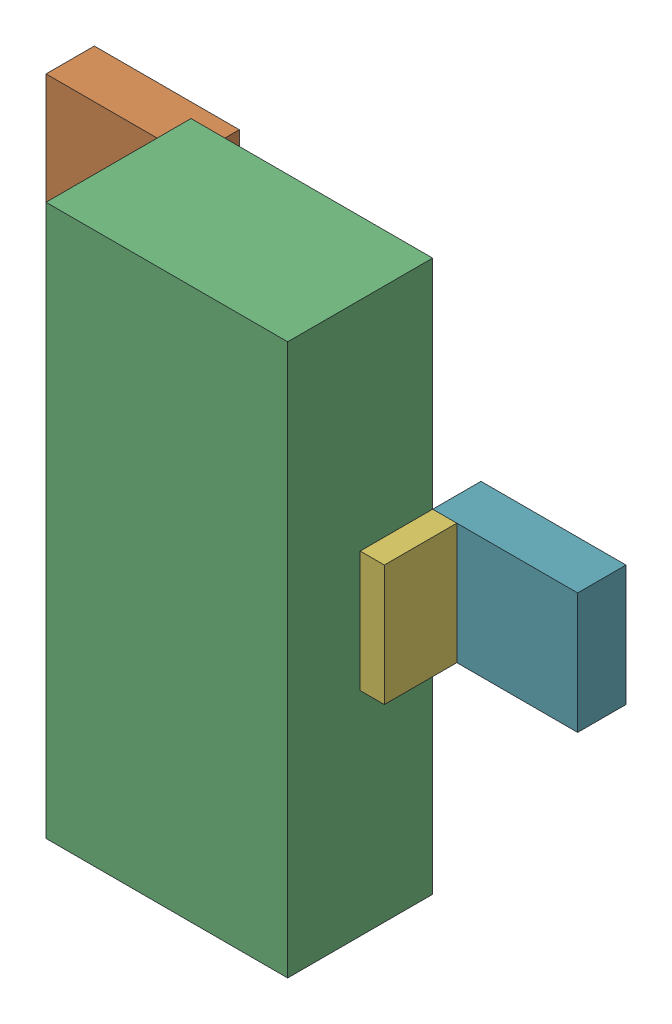
SolidWorks assembly Q5, configuration Default. Lengths in mm.
Overall size (2.79 2.9 1.02).
14 component instances, 3 part files, 0 mates.
Components (placement in the parent):
- 898052496-1: 898052496 [Default] at (26.7216 2.8829 0) size (0.76 0.64 0.25)
  - Extruded_10-1: Extruded_10 [Default] at origin size (0.76 0.64 0.25)
- 898052496-2: 898052496 [Default] at (26.7216 4.7879 0) size (0.76 0.64 0.25)
  - Extruded_10-1: Extruded_10 [Default] at origin size (0.76 0.64 0.25)
- 898052360-1: 898052360 [Default] at (27.7377 3.8354 0.254) size (1.27 2.9 0.76)
  - Extruded_11-1: Extruded_11 [Default] at origin size (1.27 2.9 0.76)
- 898052632-1: 898052632 [Default] at (27.0392 2.8829 0.254) size (0.13 0.64 0.38)
  - Extruded_12-1: Extruded_12 [Default] at origin size (0.13 0.64 0.38)
- 898052632-2: 898052632 [Default] at (27.0392 4.7879 0.254) size (0.13 0.64 0.38)
  - Extruded_12-1: Extruded_12 [Default] at origin size (0.13 0.64 0.38)
- 898052632-3: 898052632 [Default] at (28.4361 3.8227 0.254) size (0.13 0.64 0.38)
  - Extruded_12-1: Extruded_12 [Default] at origin size (0.13 0.64 0.38)
- 898052496-3: 898052496 [Default] at (28.7537 3.8227 0) size (0.76 0.64 0.25)
  - Extruded_10-1: Extruded_10 [Default] at origin size (0.76 0.64 0.25)
